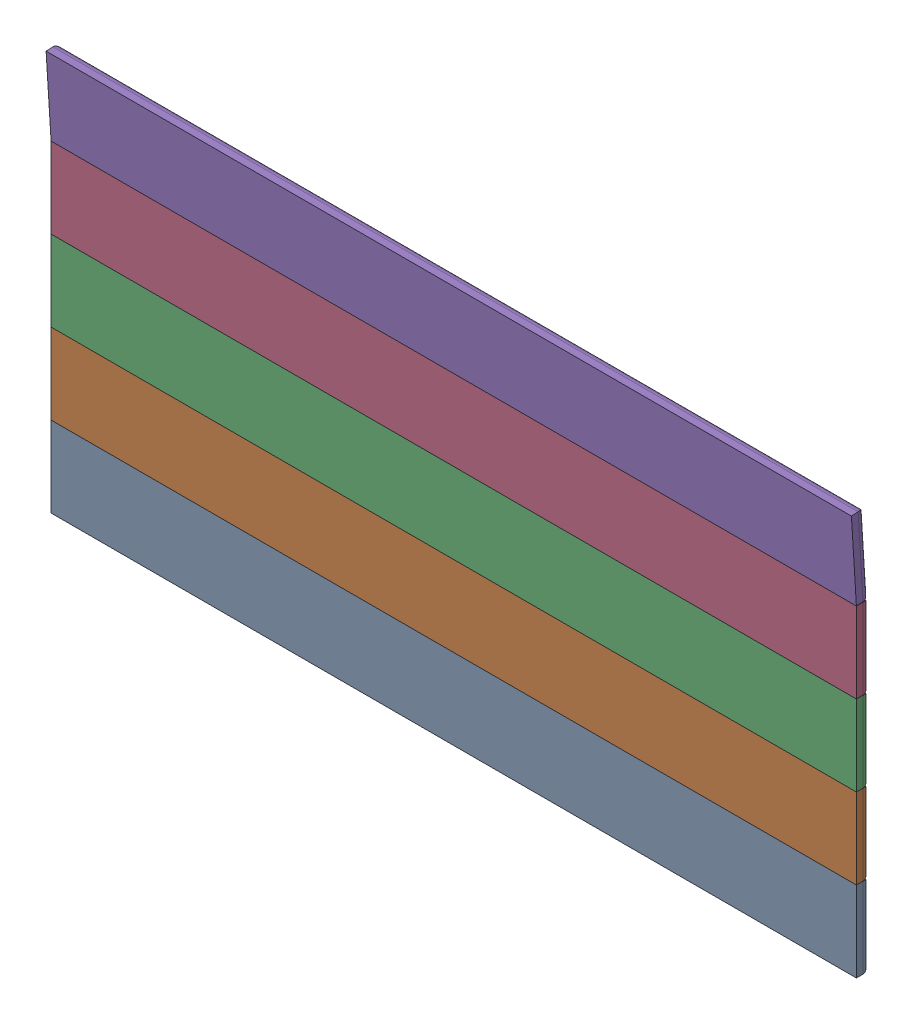
SolidWorks assembly Final Garage 2, configuration Default. Lengths in mm.
Overall size (6000 3005.03 137.07).
5 component instances, 2 part files, 19 mates.
Components (placement in the parent):
- Garage Handle 2-2: Garage Handle 2 [Default] at (0 315.3177 0) x (-1 0 0) z (0 0 -1) size (6000 600 100)
- Garage Part 2-1: Garage Part 2 [Default] at (3000 1215.3177 -100) x (-1 0 0) z (0 0 -1) size (6000 600 100)
- Garage Part 2-2: Garage Part 2 [Default] at (3000 1815.3177 -100) x (-1 0 0) z (0 0 -1) size (6000 600 100)
- Garage Part 2-3: Garage Part 2 [Default] at (3000 2415.3177 -100) x (-1 0 0) z (0 0 -1) size (6000 600 100)
- Garage Part 2-4: Garage Part 2 [Default] at (3000 3020.9223 -81.2761) x (-1 0 0) z (0 0.061776 -0.99809) size (6000 600 100)
Mates (geometry in assembly coordinates):
- Coincident1: coincident anti-aligned: line of Garage Handle 2-2 through (0 915.3177 0) axis (1 0 0); line of Garage Part 2-1 through (6000 915.3177 0) axis (-1 0 0)
- Coincident2: coincident anti-aligned: line of Garage Part 2-1 through (0 1515.3177 0) axis (1 0 0); line of Garage Part 2-2 through (6000 1515.3177 0) axis (-1 0 0)
- Coincident3: coincident anti-aligned: line of Garage Part 2-2 through (0 2115.3177 0) axis (1 0 0); line of Garage Part 2-3 through (6000 2115.3177 0) axis (-1 0 0)
- Coincident4: coincident anti-aligned: line of Garage Part 2-3 through (0 2715.3177 0) axis (1 0 0); line of Garage Part 2-4 through (6000 2715.3177 0) axis (-1 0 0)
- Coincident5: coincident: point of Garage Part 2-3; point of Garage Part 2-4
- Coincident6: coincident: point of Garage Part 2-2; point of Garage Part 2-3
- Coincident7: coincident: point of Garage Part 2-1; point of Garage Part 2-2
- Coincident8: coincident: point of Garage Handle 2-2; point of Garage Part 2-1
- Coincident10: coincident aligned: plane of Garage Part 2-3 through (6000 2115.3177 0) normal (1 0 0); plane of Garage Part 2-4 through (6000 2715.3177 0) normal (1 0 0)
- Coincident11: coincident aligned: plane of Garage Part 2-2 through (6000 1515.3177 0) normal (1 0 0); plane of Garage Part 2-4 through (6000 2715.3177 0) normal (1 0 0)
- Coincident12: coincident aligned: plane of Garage Part 2-1 through (6000 915.3177 0) normal (1 0 0); plane of Garage Part 2-4 through (6000 2715.3177 0) normal (1 0 0)
- Coincident13: coincident aligned: plane of Garage Handle 2-2 through (6000 315.3177 -100) normal (1 0 0); plane of Garage Part 2-4 through (6000 2715.3177 0) normal (1 0 0)
- Parallel1: parallel aligned: plane of Garage Part 2-4 through (6000 2715.3177 0) normal (1 0 0)
- Coincident14: coincident: unknown of Garage Handle 2-2
- Coincident15: coincident: unknown of Garage Part 2-1
- Coincident16: coincident: unknown of Garage Part 2-1
- Coincident17: coincident: unknown of Garage Part 2-2
- Coincident18: coincident: unknown of Garage Part 2-4
- Coincident19: coincident: unknown of Garage Part 2-4
